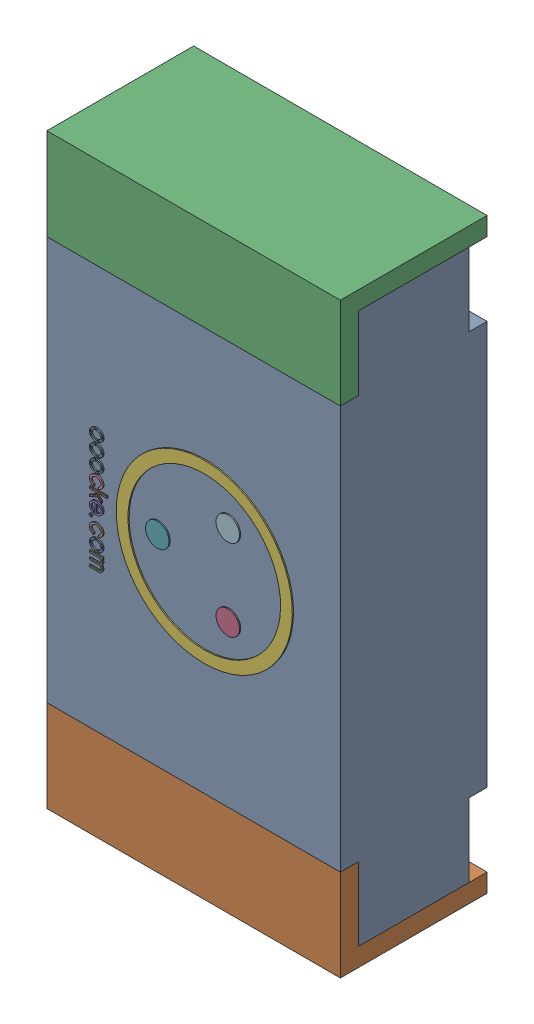
SolidWorks assembly R2, configuration 默认. Lengths in mm.
Overall size (0.8 1.6 0.41).
3 component instances, 2 part files, 0 mates.
Components (placement in the parent):
- R_0603-1: R_0603 [默认] at (85.979 93.853 -0.4115) x (0 1 0) z (0 0 -1) size (1.6 0.8 0.41)
  - R_0603-1: R_0603 [默认] at origin size (1.6 0.8 0.41)
  - LOGO__2-1: LOGO__2 [默认] at (0.0001 0.0322 -0.0016) x (-1 0 0) z (0 0 -1) size (0.48 0.55 0)
